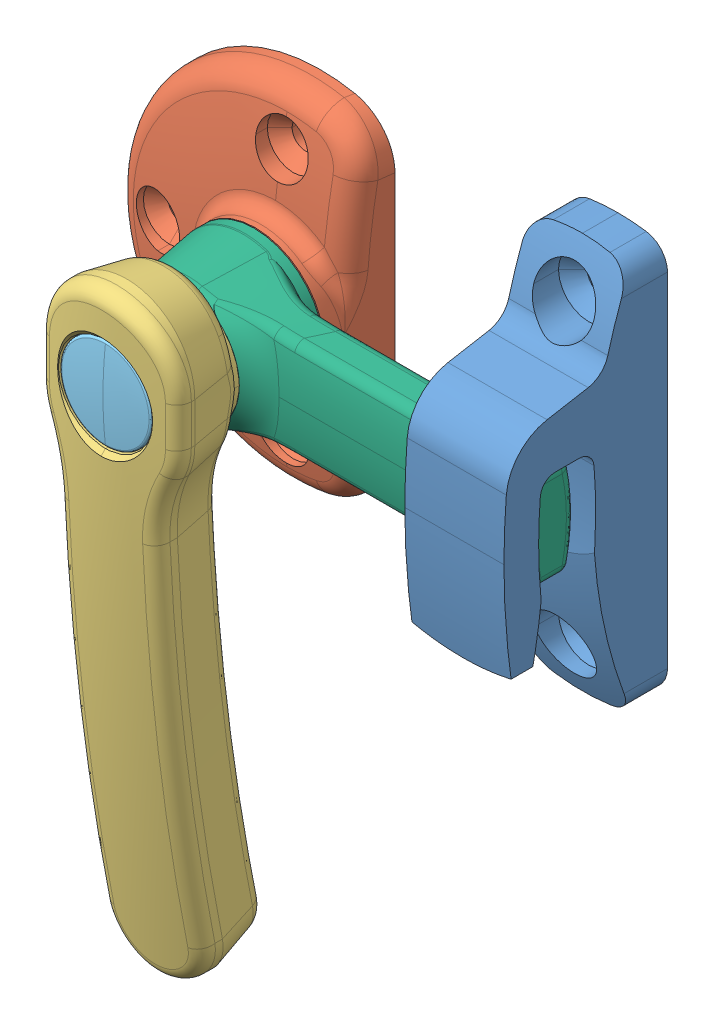
SolidWorks assembly FA-624-2-L, configuration Default. Lengths in mm.
Overall size (105.22 147.05 45.47).
8 component instances, 7 part files, 0 mates.
Components (placement in the parent):
- FA-624-2-L.STEP-1: FA-624-2-L.STEP [Default] at origin size (105.22 147.05 45.47)
  - FA-624-2__________________.STEP-1: FA-624-2__________________.STEP [Default] at (60 0 0) size (20.45 80 33)
  - FA-624-2_x_[_X__________.STEP-1: FA-624-2_x_[_X__________.STEP [Default] x (-1 0 0) z (0 0 1) size (50 70 18.88)
  - FA-624-2_n___h______hexabolt.STEP-1: FA-624-2_n___h______hexabolt.STEP [Default] at (0 0 29.4) size (28.1 125.1 26.08)
  - _Z_p___t_{___gM8_______.STEP-1: _Z_p___t_{___gM8_______.STEP [Default] at (0 0 30.9) x (0 -1 0) z (0 0 1) size (12.3 12.3 32)
  - FA-624-2_____L___b_v__________.STEP-1: FA-624-2_____L___b_v__________.STEP [Default] at (0 0 39.4) size (18.5 18.5 10.5)
  - FA-624-2_t_b_N__________.STEP-1: FA-624-2_t_b_N__________.STEP [Default] at (0 0 18.4) x (-1 0 0) z (0 0 1) size (82 30.28 22.88)
  - FA-624-2_J____________.STEP-1: FA-624-2_J____________.STEP [Default] at (0 0 0.9) x (0 -1 0) z (0 0 1) size (21.66 21.66 20)
